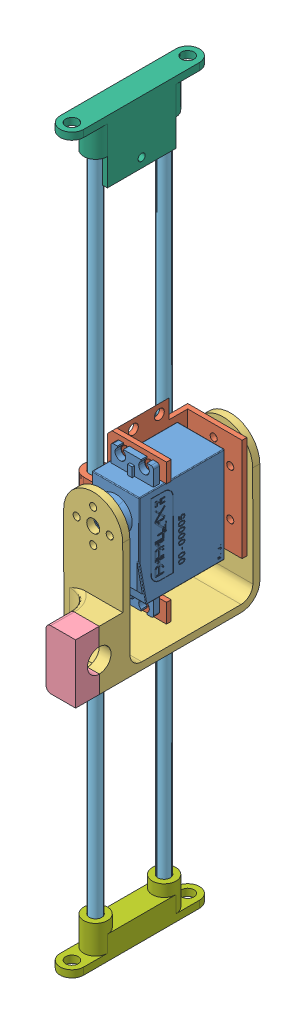
SolidWorks assembly Assemblage support + moteur, configuration Défaut. Lengths in mm.
Overall size (35.58 310 83).
8 component instances, 7 part files, 17 mates.
Components (placement in the parent):
- Parallax Servo 900-00005-1: Parallax Servo 900-00005 [Défaut] at (-15.6074 -21.0598 34.45) size (20.01 55.5 42.1)
- support_servomoteur_bras_pompe-1: support_servomoteur_bras_pompe [Défaut] at (-26.6074 1.9402 47.3) x (0 0 1) z (-1 0 0) size (39 59.4 35)
- bras_pompe_1-1: bras_pompe_1 [Défaut] at (-15.527 -41.4598 51.05) x (0.001592 -0.999999 0) z (0 0 -1) size (63 25 68)
- bras_pompe_2-1: bras_pompe_2 [Défaut] at (-15.5668 -16.4598 129.05) x (-0.001592 0.999999 0) z (0 0 1) size (25 12.5 13)
- Tige_guide_5mm_300mm-1: Tige_guide_5mm_300mm [Défaut] at (-33.6074 -160.5912 32.05) x (-0.297559 0 -0.954703) z (0.954703 0 -0.297559) size (5 300 5)
- Tige_guide_5mm_300mm-2: Tige_guide_5mm_300mm [Défaut] at (-33.6074 -160.5912 61.05) x (0.72001 0 -0.693964) z (0.693964 0 0.72001) size (5 300 5)
- support_tige_guide-1: support_tige_guide [Défaut] at (-28.6074 143.4088 27.05) x (0 0 1) z (1 0 0) size (59 26.5 10)
- support_tige_guide_top-1: support_tige_guide_top [Défaut] at (-28.6074 -166.5912 66.05) x (0 0 -1) z (1 0 0) size (59 15 10)
Mates (geometry in assembly coordinates):
- Distance4: distance = 1 mm anti-aligned: plane of Parallax Servo 900-00005-1 through (-25.6074 -21.0598 34.45) normal (-1 0 0); plane of support servomoteur-1 through (-26.6074 1.9402 47.3) normal (1 0 0)
- Coaxiale6: concentric aligned: circle of support servomoteur-1; cylinder of bras_pompe_1-1 through (-15.6074 9.0402 80.05) axis (0 0 -1) radius 2.75
- Distance2: distance = 2 mm anti-aligned: plane of bras_pompe_1-1 through (-3.027 -41.4399 25.05) normal (0 0 1); plane of support servomoteur-1 through (-28.6074 20.9402 27.05) normal (0 0 -1)
- Coïncidente7: coincident anti-aligned: plane of Parallax Servo 900-00005-1 through (-15.6074 -21.0598 61.05) normal (0 0 -1); plane of support servomoteur-1 through (-28.6074 20.9402 61.05) normal (0 0 1)
- Distance5: distance = 1.5 mm anti-aligned: plane of Parallax Servo 900-00005-1 through (-15.6074 19.4402 34.45) normal (0 1 0); plane of support servomoteur-1 through (-28.6074 20.9402 56.05) normal (0 -1 0)
- Coïncidente9: coincident aligned: plane of bras_pompe_1-1 through (-3.027 -41.4399 51.05) normal (0.999999 0.001592 0); plane of bras_pompe_2-1 through (-3.0668 -16.4399 129.05) normal (0.999999 0.001592 0)
- Coïncidente10: coincident aligned: plane of bras_pompe_1-1 through (-3.0668 -16.4399 90.05) normal (-0.001592 0.999999 0); plane of bras_pompe_2-1 through (-3.0668 -16.4399 129.05) normal (-0.001592 0.999999 0)
- Coïncidente11: coincident anti-aligned: plane of bras_pompe_1-1 through (-3.0668 -16.4399 90.05) normal (0 0 1); plane of bras_pompe_2-1 through (-3.027 -41.4399 90.05) normal (0 0 -1)
- Coïncidente13: coincident anti-aligned: plane of Tige_guide_5mm_300mm-2 through (-33.6074 139.4088 61.05) normal (0 1 0); plane of support_tige_guide-1 through (-33.6074 139.4088 61.05) normal (0 -1 0)
- Coïncidente16: coincident anti-aligned: circle of Tige_guide_5mm_300mm-1; plane of support_tige_guide-1 through (-33.6074 139.4088 32.05) normal (0 -1 0)
- Coaxiale9: concentric aligned: circle of Tige_guide_5mm_300mm-1; circle of support_tige_guide-1
- Coaxiale10: concentric aligned: circle of Tige_guide_5mm_300mm-2; circle of support_tige_guide-1
- Coaxiale11: concentric anti-aligned: circle of support_servomoteur_bras_pompe-1; cylinder of Tige_guide_5mm_300mm-1 through (-33.6074 139.4088 32.05) axis (0 -1 0) radius 2.5
- Coaxiale12: concentric aligned: circle of support_servomoteur_bras_pompe-1; cylinder of Tige_guide_5mm_300mm-2 through (-33.6074 139.4088 61.05) axis (0 -1 0) radius 2.5
- Coaxiale13: concentric anti-aligned: cylinder of Tige_guide_5mm_300mm-1 through (-33.6074 139.4088 32.05) axis (0 -1 0) radius 2.5; circle of support_tige_guide_top-1
- Coaxiale14: concentric anti-aligned: cylinder of Tige_guide_5mm_300mm-2 through (-33.6074 139.4088 61.05) axis (0 -1 0) radius 2.5; circle of support_tige_guide_top-1
- Distance6: distance = 310 mm: line of support_tige_guide-1 through (-28.6074 143.4088 22.0481) axis (0 0 1); plane of support_tige_guide_top-1 through (-33.6074 -166.5912 32.05) normal (0 -1 0)
